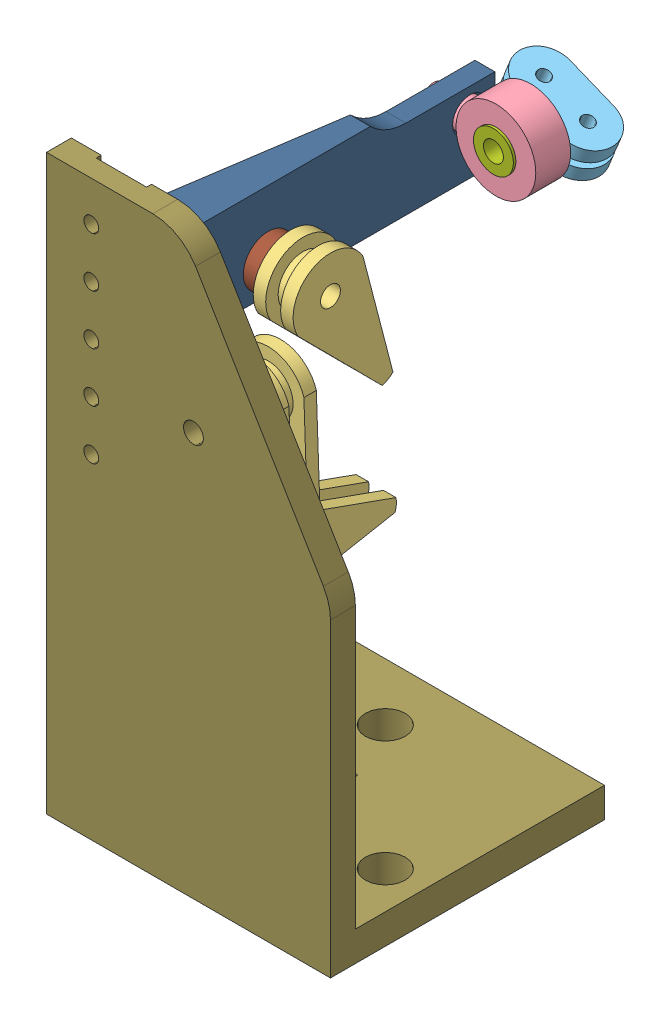
SolidWorks assembly 拉力组件右, configuration 默认. Lengths in mm.
Overall size (57 115 83.5).
16 component instances, 12 part files, 26 mates.
Components (placement in the parent):
- 拉力计-1: 拉力计 [Default] at (-15.3437 28.3156 -6) x (0 0 -1) z (0 1 0) size (25 11.8 30)
- 拉力连接件-1: 拉力连接件 [默认] at (-21.2437 27.3156 -18.5) x (0 0 1) z (-1 0 0) size (10 20 18)
- NT002滑轮-1: NT002滑轮 [默认] at (-16.2437 74.3156 -12) x (0.955567 0.294773 0) z (-0.294773 0.955567 0) size (15 8 35.78)
- NT002滑轮-2: NT002滑轮 [默认] at (-22.7437 42.3156 -18.5) x (0 -0.996885 0.07887) z (0 0.07887 0.996885) size (15 8 35.78)
- 万向绳-1: 万向绳 [默认] at (-25.0437 185.5278 -42.9711) x (0 1 0) z (-1 0 0) size (16 18.5 26.37) (flexible)
  - 万向绳2-1: 万向绳2 [默认] at (-97.2122 22.5289 -4) size (16 7 24)
  - 万向绳1-1: 万向绳1 [默认] at (-92.1831 35.2789 -0.9144) x (-0.375978 0 -0.926629) z (0 1 0) size (20 7 13.5)
  - 万向绳3-1: 万向绳3 [默认] at (-97.2122 27.0289 -4) size (11 2.5 11)
  - 万向绳4-1: 万向绳4 [默认] at (-97.2122 27.0289 -4) x (-0.837169 0 -0.546944) z (-0.546944 0 0.837169) size (8 5 8)
- NT002滑轮-3: NT002滑轮 [默认] at (-19.7437 83.3156 -28.5) x (0 0.495502 -0.868607) z (0 0.868607 0.495502) size (15 8 35.78)
- 拉力计滑轮垫片-1: 拉力计滑轮垫片 [默认] at (-25.2437 42.3156 -18.5) x (0 0.855913 0.51712) z (0 -0.51712 0.855913) size (10 2 10)
- 滑轮1垫片-1: 滑轮1垫片 [默认] at (-16.2437 74.3156 -9.5) x (0.855913 -0.51712 0) z (-0.51712 -0.855913 0) size (10 4.5 10)
- 滑轮2连接板2.0右-1: 滑轮2连接板2.0右 [默认] at (-36.7437 83.3156 -4) x (0 1 0) z (-1 0 0) size (19 70 10)
- 滑轮2垫片-1: 滑轮2垫片 [默认] at (-25.2437 83.3156 -28.5) x (0 0.855913 0.51712) z (0 -0.51712 0.855913) size (10 4.5 10)
- 拉力计滑轮垫片-2: 拉力计滑轮垫片 [默认] at (-15.2437 42.3156 -18.5) x (0 0.855913 0.51712) z (0 -0.51712 0.855913) size (10 2 10)
- 六角柱与拉力机连接板右-2: 六角柱与拉力机连接板右 [默认] at (-33.7437 -6.6844 -25) size (57 115 55)
Mates (geometry in assembly coordinates):
- 重合10: coincident anti-aligned: plane of 拉力计-1 through (-27.1437 28.3156 -6) normal (0 1 0); plane of 拉力连接件-1 through (-21.2437 28.3156 -18.5) normal (0 -1 0)
- 同心4: concentric anti-aligned: circle of 拉力计-1; circle of 拉力连接件-1
- 重合39: coincident anti-aligned: plane of 拉力连接件-1 through (-27.2437 47.3156 -23.5) normal (1 0 0); plane of 拉力计滑轮垫片-1 through (-27.2437 42.3156 -18.5) normal (-1 0 0)
- 同心13: concentric aligned: circle of 拉力连接件-1; circle of 拉力计滑轮垫片-1
- 重合40: coincident anti-aligned: plane of NT002滑轮-2 through (-25.2437 42.3156 -18.5) normal (-1 0 0); plane of 拉力计滑轮垫片-1 through (-25.2437 42.3156 -18.5) normal (1 0 0)
- 同心14: concentric anti-aligned: circle of NT002滑轮-2; circle of 拉力计滑轮垫片-1
- 重合46: coincident anti-aligned: plane of NT002滑轮-1 through (-16.2437 74.3156 -9.5) normal (0 0 1); plane of 滑轮1垫片-1 through (-16.2437 74.3156 -9.5) normal (0 0 -1)
- 重合50: coincident anti-aligned: plane of 万向绳-1/万向绳2-1 through (-30.5437 88.3156 -69) normal (-1 0 0); plane of 滑轮2连接板2.0右-1 through (-30.5437 88.3156 -69) normal (1 0 0)
- 同心18: concentric aligned: circle of 万向绳-1/万向绳2-1; circle of 滑轮2连接板2.0-1
- 重合53: coincident anti-aligned: plane of 滑轮2连接板2.0右-1 through (-29.7437 83.3156 -4) normal (1 0 0); plane of 滑轮2垫片-1 through (-29.7437 83.3156 -28.5) normal (-1 0 0)
- 同心23: concentric anti-aligned: circle of 滑轮2连接板2.0-1; circle of 滑轮2垫片-1
- 重合55: coincident anti-aligned: plane of NT002滑轮-3 through (-25.2437 83.3156 -28.5) normal (-1 0 0); plane of 滑轮2垫片-1 through (-25.2437 83.3156 -28.5) normal (1 0 0)
- 同心24: concentric aligned: circle of NT002滑轮-3; circle of 滑轮2垫片-1
- 重合59: coincident anti-aligned: plane of NT002滑轮-2 through (-17.2437 42.3156 -18.5) normal (1 0 0); plane of 拉力计滑轮垫片-2 through (-17.2437 42.3156 -18.5) normal (-1 0 0)
- 同心27: concentric aligned: circle of 拉力连接件-1; circle of 拉力计滑轮垫片-2
- 重合60: coincident anti-aligned: plane of 拉力计-1 through (-27.1437 -1.6844 -6) normal (0 -1 0); plane of 六角柱与拉力机连接板右-2 through (-33.7437 -1.6844 -25) normal (0 1 0)
- 同心28: concentric anti-aligned: circle of 拉力计-1; circle of 六角柱与拉力机连接板右-2
- 重合63: coincident anti-aligned: plane of 滑轮1垫片-1 through (-16.2437 74.3156 -5) normal (0 0 1); plane of 六角柱与拉力机连接板右-2 through (-33.7437 -6.6844 -5) normal (0 0 -1)
- 同心29: concentric anti-aligned: circle of NT002滑轮-1; circle of 滑轮1垫片-1
- 同心31: concentric anti-aligned: circle of NT002滑轮-1; circle of 六角柱与拉力机连接板右-2
- 重合66: coincident anti-aligned: plane of 滑轮2连接板2.0右-1 through (-36.7437 83.3156 -4) normal (0 0 1); plane of 六角柱与拉力机连接板右-2 through (-33.7437 -6.6844 -4) normal (0 0 -1)
- 平行3: parallel anti-aligned: plane of 万向绳-1/万向绳2-1 through (-21.0437 88.3156 -65.5) normal (0 0 1); plane of 滑轮2连接板2.0右-1 through (-29.7437 93.3156 -74) normal (0 0 -1)
- 平行4: parallel aligned: plane of 拉力计-1 through (-27.1437 28.3156 -31) normal (0 0 -1); plane of 六角柱与拉力机连接板右-2 through (-53.7437 -0.6844 -55) normal (0 0 -1)
- 重合67: coincident anti-aligned: plane of 滑轮2连接板2.0右-1 through (-39.7437 83.3156 -9) normal (-1 0 0); plane of 六角柱与拉力机连接板右-2 through (-39.7437 -6.6844 -4) normal (1 0 0)
- 同心32: concentric anti-aligned: circle of 滑轮2连接板2.0右-1; circle of 六角柱与拉力机连接板右-2
- 重合68: coincident aligned: plane of 六角柱与拉力机连接板右-2 through (-33.7437 -6.6844 0) normal (0 0 1)
